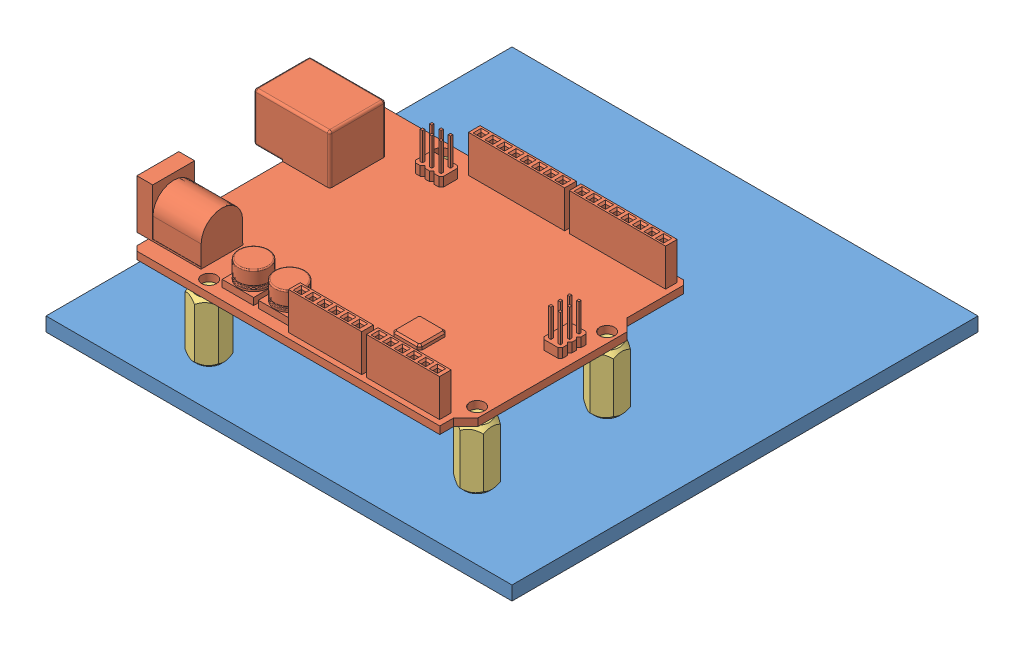
SolidWorks assembly Assem1, configuration Default. Lengths in mm.
Overall size (100 27.8 100).
6 component instances, 3 part files, 11 mates.
Components (placement in the parent):
- Side.SLDPART-1: Side.SLDPART [Default] at (47.5053 44.4582 76.6376) size (100 3 100)
- Arduino-1: Arduino [Default] at (41.5053 60.1582 92.4876) size (74.8 12.1 53.3)
- 25x.5 Aluminum Hex Female Female Standoff-1: 25x.5 Aluminum Hex Female Female Standoff [Default] at (22.5053 53.8082 116.6376) x (0.377672 0 -0.92594) z (0 -1 0) size (6.35 8.06 12.7)
- 25x.5 Aluminum Hex Female Female Standoff-2: 25x.5 Aluminum Hex Female Female Standoff [Default] at (74.9053 53.8082 83.6376) x (1 0 0) z (0 -1 0) size (6.35 8.06 12.7)
- 25x.5 Aluminum Hex Female Female Standoff-3: 25x.5 Aluminum Hex Female Female Standoff [Default] at (24.1053 53.8082 68.3376) x (0.24691 0 -0.969038) z (0 -1 0) size (6.35 8.06 12.7)
- 25x.5 Aluminum Hex Female Female Standoff-4: 25x.5 Aluminum Hex Female Female Standoff [Default] at (74.9053 53.8082 111.5376) x (1 0 0) z (0 -1 0) size (6.35 8.06 12.7)
Mates (geometry in assembly coordinates):
- Concentric1: concentric anti-aligned: cylinder of Side.SLDPART-1 through (22.5053 44.4582 116.6376) axis (0 1 0) radius 1.6; cylinder of Arduino-1 through (22.5053 93.9226 116.6376) axis (0 -1 0) radius 1.6
- Concentric2: concentric anti-aligned: cylinder of Side.SLDPART-1 through (74.9053 44.4582 83.6376) axis (0 1 0) radius 1.6; cylinder of Arduino-1 through (74.9053 93.9226 83.6376) axis (0 -1 0) radius 1.6
- Concentric3: concentric anti-aligned: cylinder of Side.SLDPART-1 through (22.5053 44.4582 116.6376) axis (0 1 0) radius 1.6; cylinder of 25x.5 Aluminum Hex Female Female Standoff-1 through (22.5053 47.4582 116.6376) axis (0 -1 0) radius 1.0287
- Concentric4: concentric: cylinder of Side.SLDPART-1 through (74.9053 44.4582 111.5376) axis (0 1 0) radius 1.6; cylinder of 25x.5 Aluminum Hex Female Female Standoff-4 through (74.9053 47.4582 111.5376) axis (0 -1 0) radius 1.0287
- Concentric5: concentric: cylinder of Side.SLDPART-1 through (24.1053 44.4582 68.3376) axis (0 1 0) radius 1.6; cylinder of 25x.5 Aluminum Hex Female Female Standoff-3 through (24.1053 61.6655 68.3376) axis (0 -1 0) radius 1.0287
- Concentric6: concentric: cylinder of Side.SLDPART-1 through (74.9053 44.4582 83.6376) axis (0 1 0) radius 1.6; cylinder of 25x.5 Aluminum Hex Female Female Standoff-2 through (74.9053 47.4582 83.6376) axis (0 -1 0) radius 1.0287
- Coincident1: coincident anti-aligned: plane of Side.SLDPART-1 through (47.5053 47.4582 76.6376) normal (0 1 0); plane of 25x.5 Aluminum Hex Female Female Standoff-2 through (74.9053 47.4582 83.6376) normal (0 -1 0)
- Coincident2: coincident anti-aligned: plane of Side.SLDPART-1 through (47.5053 47.4582 76.6376) normal (0 1 0); plane of 25x.5 Aluminum Hex Female Female Standoff-4 through (74.9053 47.4582 111.5376) normal (0 -1 0)
- Coincident3: coincident anti-aligned: plane of Side.SLDPART-1 through (47.5053 47.4582 76.6376) normal (0 1 0); plane of 25x.5 Aluminum Hex Female Female Standoff-1 through (22.5053 47.4582 116.6376) normal (0 -1 0)
- Coincident4: coincident anti-aligned: plane of Side.SLDPART-1 through (47.5053 47.4582 76.6376) normal (0 1 0); plane of 25x.5 Aluminum Hex Female Female Standoff-3 through (24.1053 47.4582 68.3376) normal (0 -1 0)
- Coincident5: coincident anti-aligned: plane of Arduino-1 through (74.5053 60.1582 65.8376) normal (0 -1 0); plane of 25x.5 Aluminum Hex Female Female Standoff-1 through (22.5053 60.1582 116.6376) normal (0 1 0)
